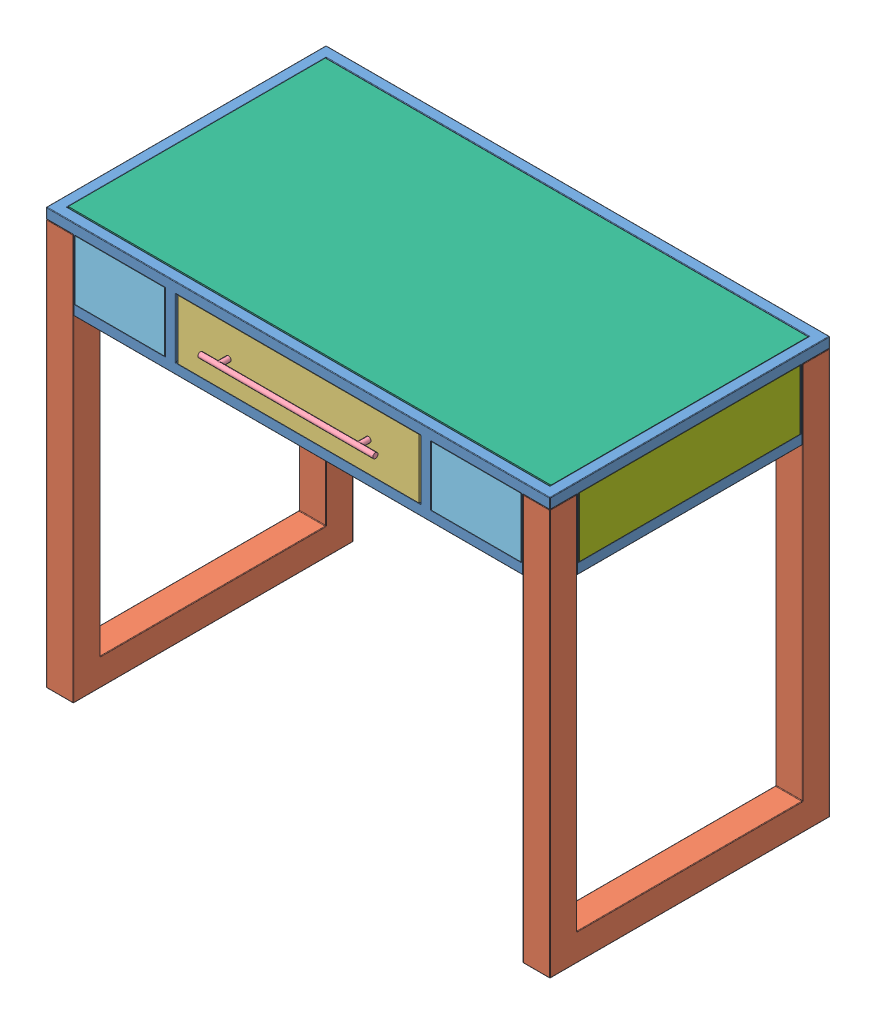
SolidWorks assembly Desk_Assembly, configuration Default. Lengths in mm.
Overall size (914.4 755.65 531.81).
14 component instances, 8 part files, 37 mates.
Components (placement in the parent):
- Desk_Frame-1: Desk_Frame [Default] at origin size (914.4 146.05 508)
- Desk_Leg-1: Desk_Leg [Default] at (0 -736.6 0) size (49.21 736.6 508)
- Desk_Leg-2: Desk_Leg [Default] at (865.1875 -736.6 0) size (49.21 736.6 508)
- Front_Drawer_Panel-1: Front_Drawer_Panel [Default] at (-218.44 -107.95 234.95) size (438.15 107.95 19.05)
- Front_Drawer_Panel-2: Front_Drawer_Panel [Default] at (-219.71 -107.95 -254) size (438.15 107.95 19.05)
- Front_Drawer_Handle-1: Front_Drawer_Handle [Default] at (0.635 -53.975 254) size (317.5 9.53 23.81)
- Front_Panel_1-1: Front_Panel_1 [Default] at (-241.3 -107.95 -254) size (162.56 107.95 19.05)
- Front_Panel_1-2: Front_Panel_1 [Default] at (-242.2525 -107.95 234.95) size (162.56 107.95 19.05)
- Front_Panel_1-3: Front_Panel_1 [Default] at (404.8125 -107.95 -254) size (162.56 107.95 19.05)
- Front_Panel_1-4: Front_Panel_1 [Default] at (404.8125 -107.95 234.95) size (162.56 107.95 19.05)
- Desk_Top-1: Desk_Top [Default] at (0 0 -0.3175) size (876.3 19.05 466.73)
- Side_Panel_1-1: Side_Panel_1 [Default] at (-438.15 -53.975 -0.3175) x (0 0 1) z (-1 0 0) size (400.05 107.95 19.05)
- Side_Panel_1-2: Side_Panel_1 [Default] at (438.15 -53.975 0.3175) x (0 0 -1) z (1 0 0) size (400.05 107.95 19.05)
- Drawer_Body-1: Drawer_Body [Default] at (2.2225 -87.3125 234.95) x (-1 0 0) z (0 0 -1) size (422.28 90.49 298.45)
Mates (geometry in assembly coordinates):
- Coincident1: coincident anti-aligned: plane of Desk_Frame-1 through (0 0 0) normal (0 -1 0); plane of Desk_Leg-1 through (0 0 0) normal (0 1 0)
- Coincident3: coincident anti-aligned: plane of Desk_Frame-1 through (0 0 0) normal (0 -1 0); plane of Desk_Leg-1 through (0 0 0) normal (0 1 0)
- Coincident8: coincident anti-aligned: plane of Desk_Frame-1 through (0 0 0) normal (0 -1 0); plane of Front_Drawer_Panel-2 through (-219.71 0 -234.95) normal (0 1 0)
- Coincident10: coincident aligned: plane of Desk_Frame-1 through (-457.2 19.05 -254) normal (0 0 -1); plane of Front_Drawer_Panel-2 through (-219.71 -107.95 -254) normal (0 0 -1)
- Coincident13: coincident anti-aligned: plane of Desk_Frame-1 through (0 0 0) normal (0 -1 0); plane of Front_Drawer_Panel-1 through (-218.44 0 254) normal (0 1 0)
- Distance3: distance = 2.54 mm anti-aligned: plane of Front_Drawer_Panel-1 through (219.71 -107.95 254) normal (1 0 0); plane of Desk_Frame-1 through (222.25 -127 234.95) normal (-1 0 0)
- Coincident15: coincident aligned: plane of Desk_Frame-1 through (-457.2 19.05 254) normal (0 0 1); plane of Front_Drawer_Panel-1 through (-218.44 -107.95 254) normal (0 0 1)
- Coincident16: coincident anti-aligned: plane of Front_Drawer_Panel-1 through (-218.44 -107.95 254) normal (0 0 1); plane of Front_Drawer_Handle-1 through (-126.365 -53.975 254) normal (0 0 -1)
- Distance4: distance = 60.325 mm aligned: plane of Front_Drawer_Handle-1 through (-158.115 -53.975 273.05) normal (-1 0 0); plane of Front_Drawer_Panel-1 through (-218.44 -107.95 254) normal (-1 0 0)
- Coincident31: coincident anti-aligned: plane of Desk_Frame-1 through (0 0 0) normal (0 -1 0); plane of Front_Panel_1-4 through (404.8125 0 254) normal (0 1 0)
- Coincident32: coincident anti-aligned: plane of Desk_Frame-1 through (404.8125 -127 -254) normal (-1 0 0); plane of Front_Panel_1-4 through (404.8125 -107.95 254) normal (1 0 0)
- Coincident33: coincident anti-aligned: plane of Desk_Frame-1 through (0 0 0) normal (0 -1 0); plane of Front_Panel_1-3 through (404.8125 0 -234.95) normal (0 1 0)
- Coincident34: coincident anti-aligned: plane of Desk_Frame-1 through (404.8125 -127 -254) normal (-1 0 0); plane of Front_Panel_1-3 through (404.8125 -107.95 -234.95) normal (1 0 0)
- Coincident35: coincident aligned: plane of Desk_Frame-1 through (-457.2 19.05 -254) normal (0 0 -1); plane of Front_Panel_1-3 through (404.8125 -107.95 -254) normal (0 0 -1)
- Coincident36: coincident aligned: plane of Desk_Frame-1 through (-457.2 19.05 254) normal (0 0 1); plane of Front_Panel_1-4 through (404.8125 -107.95 254) normal (0 0 1)
- Coincident37: coincident anti-aligned: plane of Desk_Frame-1 through (0 0 0) normal (0 -1 0); plane of Front_Panel_1-2 through (-242.2525 0 254) normal (0 1 0)
- Coincident38: coincident anti-aligned: plane of Desk_Frame-1 through (-404.8125 -127 254) normal (1 0 0); plane of Front_Panel_1-2 through (-404.8125 -107.95 254) normal (-1 0 0)
- Coincident39: coincident aligned: plane of Desk_Frame-1 through (-457.2 19.05 254) normal (0 0 1); plane of Front_Panel_1-2 through (-242.2525 -107.95 254) normal (0 0 1)
- Coincident40: coincident anti-aligned: plane of Desk_Frame-1 through (0 0 0) normal (0 -1 0); plane of Front_Panel_1-1 through (-241.3 0 -234.95) normal (0 1 0)
- Coincident41: coincident anti-aligned: plane of Desk_Frame-1 through (-241.3 -127 -234.95) normal (-1 0 0); plane of Front_Panel_1-1 through (-241.3 -107.95 -234.95) normal (1 0 0)
- Coincident43: coincident aligned: plane of Desk_Frame-1 through (-457.2 19.05 -254) normal (0 0 -1); plane of Front_Panel_1-1 through (-241.3 -107.95 -254) normal (0 0 -1)
- Coincident44: coincident anti-aligned: plane of Desk_Frame-1 through (0 0 0) normal (0 -1 0); plane of Front_Drawer_Panel-3 through (-320.5775 0 -3.7791) normal (0 1 0)
- Coincident46: coincident aligned: plane of Desk_Frame-1 through (0 19.05 0) normal (0 1 0); plane of Desk_Top-1 through (0 19.05 -0.3175) normal (0 1 0)
- Coincident47: coincident anti-aligned: plane of Desk_Frame-1 through (-438.15 19.05 234.95) normal (1 0 0); plane of Desk_Top-1 through (-438.15 19.05 233.045) normal (-1 0 0)
- Coincident49: coincident aligned: plane of Desk_Frame-1 through (-457.2 19.05 254) normal (-1 0 0); plane of Side_Panel_1-1 through (-457.2 -53.975 -0.3175) normal (-1 0 0)
- Coincident51: coincident anti-aligned: plane of Desk_Frame-1 through (-438.15 -107.95 -254.002) normal (0 1 0); plane of Side_Panel_1-1 through (-457.2 -107.95 -200.3425) normal (0 -1 0)
- Distance7: distance = 1.27 mm anti-aligned: plane of Side_Panel_1-1 through (-457.2 -107.95 -200.3425) normal (0 0 -1); plane of Desk_Frame-1 through (-457.2 -127 -201.6125) normal (0 0 1)
- Coincident53: coincident anti-aligned: plane of Desk_Frame-1 through (0 0 0) normal (0 -1 0); plane of Side_Panel_1-2 through (457.2 0 200.3425) normal (0 1 0)
- Coincident55: coincident aligned: plane of Desk_Frame-1 through (457.2 19.05 254) normal (1 0 0); plane of Side_Panel_1-2 through (457.2 -53.975 0.3175) normal (1 0 0)
- Distance8: distance = 1.27 mm anti-aligned: plane of Side_Panel_1-2 through (457.2 -107.95 200.3425) normal (0 0 1); plane of Desk_Frame-1 through (457.2 -127 201.6125) normal (0 0 -1)
- Distance9: distance = 1.27 mm anti-aligned: plane of Desk_Top-1 through (-438.15 19.05 -233.68) normal (0 0 -1); plane of Desk_Frame-1 through (-438.15 19.05 -234.95) normal (0 0 1)
- Coincident58: coincident anti-aligned: plane of Front_Drawer_Panel-1 through (-218.44 -107.95 234.95) normal (0 0 -1); plane of Drawer_Body-1 through (2.2225 -87.3125 234.95) normal (0 0 1)
- Distance10: distance = 6.35 mm: line of Drawer_Body-1 through (184.0085 -101.6 234.95) axis (-1 0 0); line of Desk_Frame-1 through (-223.266 -107.95 234.95) axis (-1 0 0)
- Distance12: distance = 53.975 mm: line of Front_Drawer_Handle-1 through (159.385 -53.975 277.8125) axis (0 0 -1); line of Front_Drawer_Panel-1 through (-218.44 -107.95 254) axis (1 0 0)
- Distance13: distance = 9.525 mm aligned: plane of Drawer_Body-1 through (-208.915 -11.1125 -50.8) normal (-1 0 0); plane of Front_Drawer_Panel-1 through (-218.44 -107.95 254) normal (-1 0 0)
- Coincident65: coincident aligned: plane of Desk_Frame-1 through (-457.2 19.05 254) normal (-1 0 0); plane of Side_Panel_1-1 through (-457.2 -53.975 -0.3175) normal (-1 0 0)
- Distance14: distance = 2.54 mm anti-aligned: plane of Front_Drawer_Panel-2 through (-219.71 -107.95 -234.95) normal (-1 0 0); plane of Desk_Frame-1 through (-222.25 -127 -234.95) normal (1 0 0)
